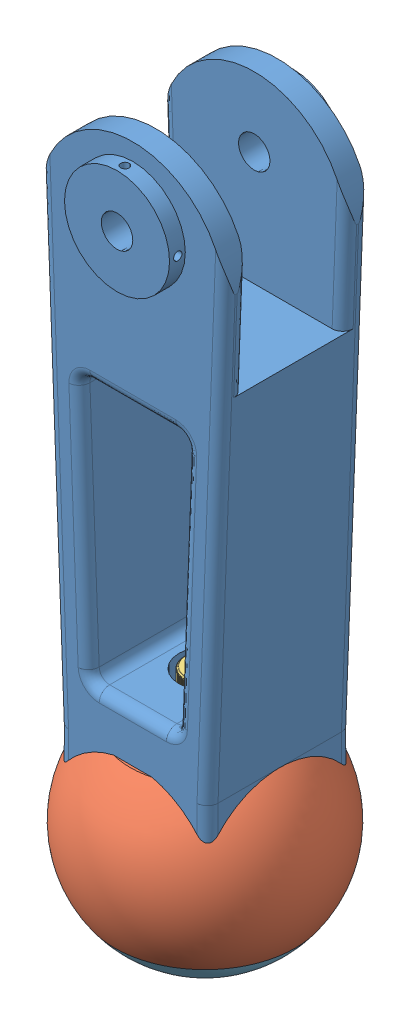
SolidWorks assembly Shin_Assembly_2.0, configuration Default. Lengths in mm.
Overall size (43.18 142.24 43.18).
6 component instances, 6 part files, 13 mates.
Components (placement in the parent):
- Shin_body_5-1: Shin_body_5 [Default] at origin size (35.56 114.77 34.04)
- Ball_top-1: Ball_top [Default] at (0 -0.0004 13.97) size (43.18 28.74 43.18)
- 90128A946_Zinc-Plated Alloy Steel Socket Head Screw-1: 90128A946_Zinc-Plated Alloy Steel Socket Head Screw [90128A946] at (0 12.2555 13.97) x (1 0 0) z (0 1 0) size (7.95 7.95 27.71)
- Washer-1: Washer [Default] at (0 2.0653 13.97) size (20.32 3.81 20.32)
- Ball_bottom-1: Ball_bottom [Default] at (0 -0.0004 13.97) size (34.92 19.81 34.92)
- 90480A195_Low-Strength Steel Hex Nut-1: 90480A195_Low-Strength Steel Hex Nut [90480A195] at (0 0.4778 13.97) size (9.53 3.79 11)
Mates (geometry in assembly coordinates):
- Concentric1: concentric aligned: circle of Shin_body_5-1; circle of Ball_top-1
- Coincident1: coincident anti-aligned: plane of Shin_body_5-1 through (0 16.0353 27.94) normal (0 -1 0); plane of Ball_top-1 through (0 16.0353 13.97) normal (0 1 0)
- Coincident2: coincident aligned: plane of Shin_body_5-1 through (0 0 0) normal (0 0 1)
- Coincident3: coincident aligned: plane of Shin_body_5-1 through (0 0 0) normal (0 1 0)
- Coincident4: coincident aligned: plane of Shin_body_5-1 through (0 0 0) normal (1 0 0)
- Concentric2: concentric: circle of Shin_body_5-1; circle of 90128A946_Zinc-Plated Alloy Steel Socket Head Screw-1
- Coincident5: coincident anti-aligned: plane of Shin_body_5-1 through (0 20.955 13.97) normal (0 1 0); plane of 90128A946_Zinc-Plated Alloy Steel Socket Head Screw-1 through (0 20.955 11.557) normal (0 -1 0)
- Concentric3: concentric: circle of Ball_top-1; circle of Washer-1
- Coincident6: coincident anti-aligned: plane of Shin_body_5-1 through (0 5.8753 13.97) normal (0 -1 0); plane of Washer-1 through (0 5.8753 13.97) normal (0 1 0)
- Concentric4: concentric: cone of Ball_top-1; cone of 90480A195_Low-Strength Steel Hex Nut-1 through (0 2.0653 13.97) axis (0 -1 0)
- Coincident8: coincident anti-aligned: plane of Washer-1 through (0 2.0653 13.97) normal (0 -1 0); plane of 90480A195_Low-Strength Steel Hex Nut-1 through (-4.7625 2.0653 11.2204) normal (0 1 0)
- Concentric5: concentric: circle of Ball_top-1; circle of Ball_bottom-1
- Coincident9: coincident anti-aligned: plane of Ball_top-1 through (0 -12.7004 13.97) normal (0 -1 0); plane of Ball_bottom-1 through (0 -12.7004 13.97) normal (0 1 0)
